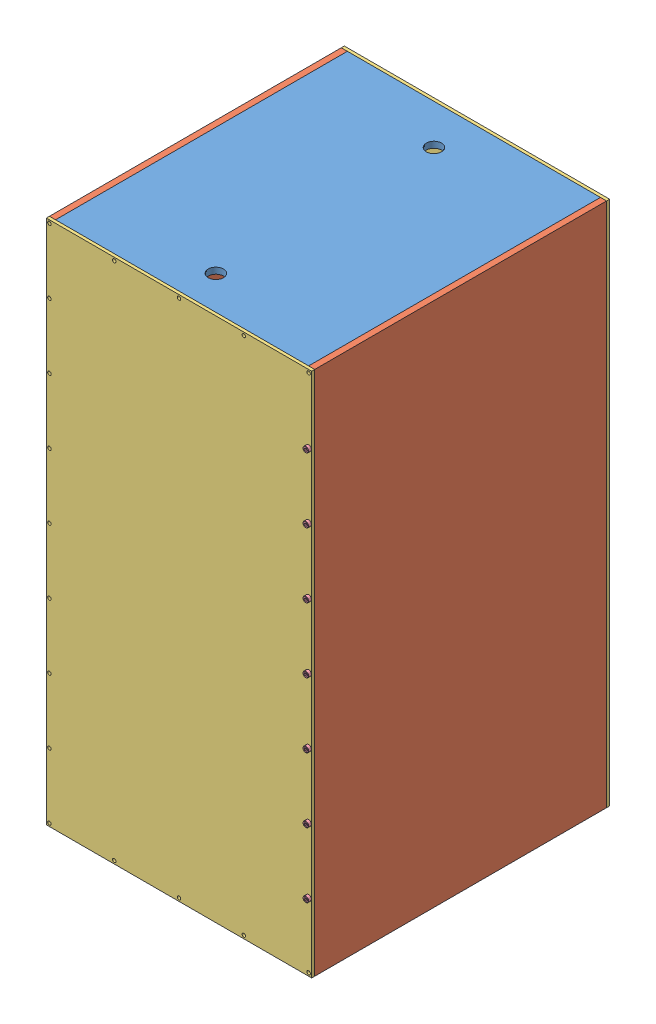
SolidWorks assembly Enclosure_assy, configuration Default. Lengths in mm.
Overall size (260.76 515 295).
14 component instances, 4 part files, 36 mates.
Components (placement in the parent):
- Assem48^Enclosure_assy-1: Assem48^Enclosure_assy [Default] at origin size (248.01 5.99 286.01) (virtual)
  - Enclosure_Bottom-1: Enclosure_Bottom [Default] at origin size (248.01 5.99 286.01)
- Enclosure_Front_Rear-1: Enclosure_Front_Rear [Default] at (0 0 -286.0056) x (0 0 1) z (-1 0 0) size (286.01 515 5.99)
- Enclosure_Front_Rear-2: Enclosure_Front_Rear [Default] at (248.0112 0 0) x (0 0 -1) z (1 0 0) size (286.01 515 5.99)
- Enclosure_Side-1: Enclosure_Side [Default] at (-5.9944 0 -289.0028) size (260 515 3)
- Enclosure_Side-2: Enclosure_Side [Default] at (-5.9944 0 0) size (260 515 3)
- socket head cap screw_am-3: socket head cap screw_am [B18.3.1M - 3 x 0.5 x 25 Hex SHCS -- 18NHX] at (251.0056 448.375 5.9972) x (0 0 -1) z (0.866025 -0.5 0) size (28 5.5 5.5)
- socket head cap screw_am-4: socket head cap screw_am [B18.3.1M - 3 x 0.5 x 25 Hex SHCS -- 18NHX] at (251.0056 384.75 5.9972) x (0 0 -1) z (0.866025 -0.5 0) size (28 5.5 5.5)
- socket head cap screw_am-5: socket head cap screw_am [B18.3.1M - 3 x 0.5 x 25 Hex SHCS -- 18NHX] at (251.0056 321.125 5.9972) x (0 0 -1) z (0.866025 -0.5 0) size (28 5.5 5.5)
- socket head cap screw_am-6: socket head cap screw_am [B18.3.1M - 3 x 0.5 x 25 Hex SHCS -- 18NHX] at (251.0056 257.5 5.9972) x (0 0 -1) z (0.866025 -0.5 0) size (28 5.5 5.5)
- socket head cap screw_am-7: socket head cap screw_am [B18.3.1M - 3 x 0.5 x 25 Hex SHCS -- 18NHX] at (251.0056 193.875 5.9972) x (0 0 -1) z (0.866025 -0.5 0) size (28 5.5 5.5)
- socket head cap screw_am-8: socket head cap screw_am [B18.3.1M - 3 x 0.5 x 25 Hex SHCS -- 18NHX] at (251.0056 130.25 5.9972) x (0 0 -1) z (0.866025 -0.5 0) size (28 5.5 5.5)
- socket head cap screw_am-9: socket head cap screw_am [B18.3.1M - 3 x 0.5 x 25 Hex SHCS -- 18NHX] at (251.0056 66.625 5.9972) x (0 0 -1) z (0.866025 -0.5 0) size (28 5.5 5.5)
- Enclosure_Bottom-2: Enclosure_Bottom [Top] at (0 509.0056 0) size (248.01 5.99 286.01)
Mates (geometry in assembly coordinates):
- Coincident10: coincident: plane of assembly; plane of assembly; plane of Enclosure_Front_Rear-2 through (254.0056 0 0) normal (1 0 0); plane of Enclosure_Side-1 through (254.0056 0 -286.0056) normal (1 0 0)
- Coincident13: coincident: plane of assembly; plane of assembly; plane of Enclosure_Front_Rear-2 through (254.0056 0 0) normal (1 0 0); plane of Enclosure_Side-2 through (254.0056 0 2.9972) normal (1 0 0)
- Coincident17: coincident: plane of assembly; plane of assembly; plane of Enclosure_Side-2 through (-5.9944 0 2.9972) normal (0 0 1); plane of socket head cap screw_am-3 through (252.3806 450.7566 2.9972) normal (0 0 -1)
- Parallel3: parallel: plane of assembly; plane of assembly; plane of Enclosure_Side-2 through (-5.9944 515 2.9972) normal (0 1 0); plane of socket head cap screw_am-3 through (251.7446 449.655 4.6972) normal (0 -1 0)
- Concentric3: concentric: cylinder of assembly; cylinder of assembly; cylinder of Enclosure_Side-2 through (251.0056 448.375 2.9972) axis (0 0 1) radius 1.7; cylinder of socket head cap screw_am-3 through (251.0056 448.375 37.7472) axis (0 0 1) radius 1.5
- Coincident18: coincident: plane of assembly; plane of assembly; plane of Enclosure_Side-2 through (-5.9944 0 2.9972) normal (0 0 1); plane of socket head cap screw_am-4 through (252.3806 387.1316 2.9972) normal (0 0 -1)
- Parallel4: parallel: plane of assembly; plane of assembly; plane of Enclosure_Side-2 through (-5.9944 515 2.9972) normal (0 1 0); plane of socket head cap screw_am-4 through (251.7446 386.03 4.6972) normal (0 -1 0)
- Concentric4: concentric: cylinder of assembly; cylinder of assembly; cylinder of Enclosure_Side-2 through (251.0056 384.75 2.9972) axis (0 0 1) radius 1.7; cylinder of socket head cap screw_am-4 through (251.0056 384.75 37.7472) axis (0 0 1) radius 1.5
- Coincident19: coincident: plane of assembly; plane of assembly; plane of Enclosure_Side-2 through (-5.9944 0 2.9972) normal (0 0 1); plane of socket head cap screw_am-5 through (252.3806 323.5066 2.9972) normal (0 0 -1)
- Parallel5: parallel: plane of assembly; plane of assembly; plane of Enclosure_Side-2 through (-5.9944 515 2.9972) normal (0 1 0); plane of socket head cap screw_am-5 through (251.7446 322.405 4.6972) normal (0 -1 0)
- Concentric5: concentric: cylinder of assembly; cylinder of assembly; cylinder of Enclosure_Side-2 through (251.0056 321.125 2.9972) axis (0 0 1) radius 1.7; cylinder of socket head cap screw_am-5 through (251.0056 321.125 37.7472) axis (0 0 1) radius 1.5
- Coincident20: coincident: plane of assembly; plane of assembly; plane of Enclosure_Side-2 through (-5.9944 0 2.9972) normal (0 0 1); plane of socket head cap screw_am-6 through (252.3806 259.8816 2.9972) normal (0 0 -1)
- Parallel6: parallel: plane of assembly; plane of assembly; plane of Enclosure_Side-2 through (-5.9944 515 2.9972) normal (0 1 0); plane of socket head cap screw_am-6 through (251.7446 258.78 4.6972) normal (0 -1 0)
- Concentric6: concentric: cylinder of assembly; cylinder of assembly; cylinder of Enclosure_Side-2 through (251.0056 257.5 2.9972) axis (0 0 1) radius 1.7; cylinder of socket head cap screw_am-6 through (251.0056 257.5 37.7472) axis (0 0 1) radius 1.5
- Coincident21: coincident: plane of assembly; plane of assembly; plane of Enclosure_Side-2 through (-5.9944 0 2.9972) normal (0 0 1); plane of socket head cap screw_am-7 through (252.3806 196.2566 2.9972) normal (0 0 -1)
- Parallel7: parallel: plane of assembly; plane of assembly; plane of Enclosure_Side-2 through (-5.9944 515 2.9972) normal (0 1 0); plane of socket head cap screw_am-7 through (251.7446 195.155 4.6972) normal (0 -1 0)
- Concentric7: concentric: cylinder of assembly; cylinder of assembly; cylinder of Enclosure_Side-2 through (251.0056 193.875 2.9972) axis (0 0 1) radius 1.7; cylinder of socket head cap screw_am-7 through (251.0056 193.875 37.7472) axis (0 0 1) radius 1.5
- Coincident22: coincident: plane of assembly; plane of assembly; plane of Enclosure_Side-2 through (-5.9944 0 2.9972) normal (0 0 1); plane of socket head cap screw_am-8 through (252.3806 132.6316 2.9972) normal (0 0 -1)
- Parallel8: parallel: plane of assembly; plane of assembly; plane of Enclosure_Side-2 through (-5.9944 515 2.9972) normal (0 1 0); plane of socket head cap screw_am-8 through (251.7446 131.53 4.6972) normal (0 -1 0)
- Concentric8: concentric: cylinder of assembly; cylinder of assembly; cylinder of Enclosure_Side-2 through (251.0056 130.25 2.9972) axis (0 0 1) radius 1.7; cylinder of socket head cap screw_am-8 through (251.0056 130.25 37.7472) axis (0 0 1) radius 1.5
- Coincident23: coincident: plane of assembly; plane of assembly; plane of Enclosure_Side-2 through (-5.9944 0 2.9972) normal (0 0 1); plane of socket head cap screw_am-9 through (252.3806 69.0066 2.9972) normal (0 0 -1)
- Parallel9: parallel: plane of assembly; plane of assembly; plane of Enclosure_Side-2 through (-5.9944 515 2.9972) normal (0 1 0); plane of socket head cap screw_am-9 through (251.7446 67.905 4.6972) normal (0 -1 0)
- Concentric9: concentric: cylinder of assembly; cylinder of assembly; cylinder of Enclosure_Side-2 through (251.0056 66.625 2.9972) axis (0 0 1) radius 1.7; cylinder of socket head cap screw_am-9 through (251.0056 66.625 37.7472) axis (0 0 1) radius 1.5
- Coincident24: coincident: plane of assembly; plane of assembly; plane of Enclosure_Front_Rear-1 through (-5.9944 515 -286.0056) normal (0 1 0); plane of Enclosure_Bottom-2 through (0 515 0) normal (0 1 0)
- Coincident25: coincident: plane of assembly; plane of assembly; plane of Enclosure_Front_Rear-1 through (0 0 -286.0056) normal (1 0 0); plane of Enclosure_Bottom-2 through (0 515 0) normal (-1 0 0)
- Coincident26: coincident: plane of assembly; plane of assembly; plane of Enclosure_Side-2 through (-5.9944 0 0) normal (0 0 -1); plane of Enclosure_Bottom-2 through (0 515 0) normal (0 0 1)
- Coincident27: coincident: plane of assembly; plane of assembly; plane of Assem48^Enclosure_assy-1/Enclosure_Bottom-1 through (0 5.9944 0) normal (-1 0 0); plane of Enclosure_Front_Rear-1 through (0 0 -286.0056) normal (1 0 0)
- Coincident28: coincident: plane of assembly; plane of assembly; plane of Assem48^Enclosure_assy-1/Enclosure_Bottom-1 through (0 0 0) normal (0 -1 0); plane of Enclosure_Front_Rear-1 through (-5.9944 0 -286.0056) normal (0 -1 0)
- Coincident29: coincident: plane of assembly; plane of assembly; plane of Assem48^Enclosure_assy-1/Enclosure_Bottom-1 through (0 5.9944 -286.0056) normal (0 0 -1); plane of Enclosure_Front_Rear-1 through (-5.9944 0 -286.0056) normal (0 0 -1)
- Coincident30: coincident: plane of assembly; plane of assembly; plane of Assem48^Enclosure_assy-1/Enclosure_Bottom-1 through (248.0112 5.9944 0) normal (1 0 0); plane of Enclosure_Front_Rear-2 through (248.0112 0 0) normal (-1 0 0)
- Coincident31: coincident: plane of assembly; plane of assembly; plane of Assem48^Enclosure_assy-1/Enclosure_Bottom-1 through (0 5.9944 -286.0056) normal (0 0 -1); plane of Enclosure_Front_Rear-2 through (254.0056 0 -286.0056) normal (0 0 -1)
- Coincident32: coincident: plane of assembly; plane of assembly; plane of Assem48^Enclosure_assy-1/Enclosure_Bottom-1 through (0 0 0) normal (0 -1 0); plane of Enclosure_Front_Rear-2 through (254.0056 0 0) normal (0 -1 0)
- Coincident33: coincident: plane of assembly; plane of assembly; plane of Assem48^Enclosure_assy-1/Enclosure_Bottom-1 through (0 5.9944 -286.0056) normal (0 0 -1); plane of Enclosure_Side-1 through (-5.9944 0 -286.0056) normal (0 0 1)
- Coincident34: coincident: plane of assembly; plane of assembly; plane of Assem48^Enclosure_assy-1/Enclosure_Bottom-1 through (0 0 0) normal (0 -1 0); plane of Enclosure_Side-1 through (-5.9944 0 -286.0056) normal (0 -1 0)
- Coincident35: coincident: plane of assembly; plane of assembly; plane of Assem48^Enclosure_assy-1/Enclosure_Bottom-1 through (0 5.9944 0) normal (0 0 1); plane of Enclosure_Side-2 through (-5.9944 0 0) normal (0 0 -1)
- Coincident36: coincident: plane of assembly; plane of assembly; plane of Assem48^Enclosure_assy-1/Enclosure_Bottom-1 through (0 0 0) normal (0 -1 0); plane of Enclosure_Side-2 through (-5.9944 0 2.9972) normal (0 -1 0)
